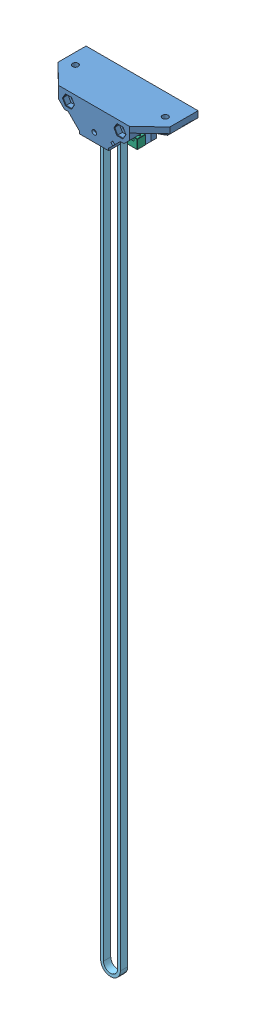
SolidWorks assembly axis-idler-assembly, configuration Default. Lengths in mm.
Overall size (77.25 525.6 33).
8 component instances, 7 part files, 22 mates.
Components (placement in the parent):
- Idler-bracket-1: Idler-bracket [Default] x (0 0 -1) z (1 0 0) size (33 34.75 77.25)
- idler-bearing-1: idler-bearing [Default] x (0 0 -1) z (1 0 0) size (4 10 10)
- idler-bearing-2: idler-bearing [Default] at (0 0 22.4) x (0 0 -1) z (1 0 0) size (4 10 10)
- idler-rod-1: idler-rod [Default] x (0 0 -1) z (1 0 0) size (25 5 5)
- timing-pulley-1: timing-pulley [Default] at (-499.0739 344.0495 0) x (0 0 -1) z (0.355713 -0.934595 0) size (16 17 17)
- Belt-1: Belt [Default] at (0 0 0.26) x (0 0 -1) z (1 0 0) size (5 516.7 13.7)
- KW-10-Mechanical-endstop-1: KW-10-Mechanical-endstop [Default] at (0 521.5 -208.15) x (-1 0 0) z (0 0 1) size (12.8 11 5.7)
- magnet-4-15-5-1: magnet-4-15-5 [Default] at (-16 528 -194.5) x (0.988109 0 -0.153754) z (-0.153754 0 -0.988109) size (15 5 15)
Mates (geometry in assembly coordinates):
- Coincident1: coincident aligned: plane of Idler-bracket-1 through (0 0 0) normal (1 0 0); plane of assembly through (0 0 0) normal (1 0 0)
- Coincident2: coincident aligned: plane of Idler-bracket-1; plane of assembly through (0 0 0) normal (0 1 0)
- Coincident3: coincident anti-aligned: plane of Idler-bracket-1 through (0 0 0) normal (0 0 -1); plane of assembly through (0 0 0) normal (0 0 1)
- Coincident5: coincident aligned: plane of Idler-bracket-1 through (0 0 0) normal (0 0 -1); plane of idler-bearing-1 through (0 0 0) normal (0 0 -1)
- Coincident6: coincident aligned: plane of Idler-bracket-1 through (0 0 0) normal (1 0 0); plane of idler-bearing-1 through (0 0 0) normal (1 0 0)
- Coincident7: coincident aligned: plane of Idler-bracket-1; plane of idler-bearing-1
- Coincident10: coincident aligned: plane of idler-bearing-2; plane of assembly through (0 0 0) normal (0 1 0)
- Coincident11: coincident anti-aligned: plane of Idler-bracket-1 through (0 534 -185.3) normal (0 0 -1); plane of idler-bearing-2 through (0 534 -185.3) normal (0 0 1)
- Coincident12: coincident anti-aligned: plane of timing-pulley-1; plane of assembly through (0 0 0) normal (0 0 1)
- Coincident15: coincident anti-aligned: plane of idler-rod-1 through (0 0 0) normal (0 0 -1); plane of assembly through (0 0 0) normal (0 0 1)
- Coincident16: coincident anti-aligned: plane of idler-rod-1 through (0 0 0) normal (0 0 -1); plane of assembly through (0 0 0) normal (0 0 1)
- Coincident18: coincident aligned: plane of idler-rod-1; plane of assembly through (0 0 0) normal (0 1 0)
- Concentric1: concentric aligned: cylinder of Idler-bracket-1 through (0 534 -185) axis (0 0 -1) radius 5.125; cylinder of idler-bearing-2 through (0 534 -185.3) axis (0 0 -1) radius 5
- Concentric2: concentric anti-aligned: cylinder of idler-bearing-1 through (0 534 -207.7) axis (0 0 -1) radius 2.5; cylinder of idler-rod-1 through (0 534 -211) axis (0 0 1) radius 2.5
- Concentric3: concentric anti-aligned: cylinder of idler-rod-1 through (0 534 -211) axis (0 0 1) radius 2.5; cylinder of timing-pulley-1 through (0 534 -190.5) axis (0 0 -1) radius 2.5
- Concentric4: concentric anti-aligned: cylinder of timing-pulley-1 through (0 534 -172.7452) axis (0 0 1) radius 4.85; cylinder of Belt-1 through (0 534 -193.24) axis (0 0 -1) radius 4.85
- Distance1: distance = 1 mm anti-aligned: plane of timing-pulley-1 through (0 534 -199.24) normal (0 0 1); plane of Belt-1 through (0 534 -198.24) normal (0 0 -1)
- Concentric5: concentric aligned: cylinder of Idler-bracket-1 through (-3.25 520 -211) axis (0 0 -1) radius 1; cylinder of KW-10-Mechanical-endstop-1 through (-3.25 520 -205.3) axis (0 0 -1) radius 1
- Concentric6: concentric aligned: cylinder of Idler-bracket-1 through (3.25 520 -211) axis (0 0 -1) radius 1; cylinder of KW-10-Mechanical-endstop-1 through (3.25 520 -205.3) axis (0 0 -1) radius 1
- Coincident19: coincident anti-aligned: plane of Idler-bracket-1 through (0 0 -211) normal (0 0 1); plane of KW-10-Mechanical-endstop-1 through (-6.4 521.5 -211) normal (0 0 -1)
- Concentric7: concentric aligned: cylinder of Idler-bracket-1 through (-16 530.5 -194.5) axis (0 1 0) radius 1.875; cylinder of magnet-4-15-5-1 through (-16 525.5 -194.5) axis (0 1 0) radius 2
- Coincident20: coincident anti-aligned: plane of Idler-bracket-1 through (-16 530.5 -194.5) normal (0 -1 0); plane of magnet-4-15-5-1 through (-16 530.5 -194.5) normal (0 1 0)
